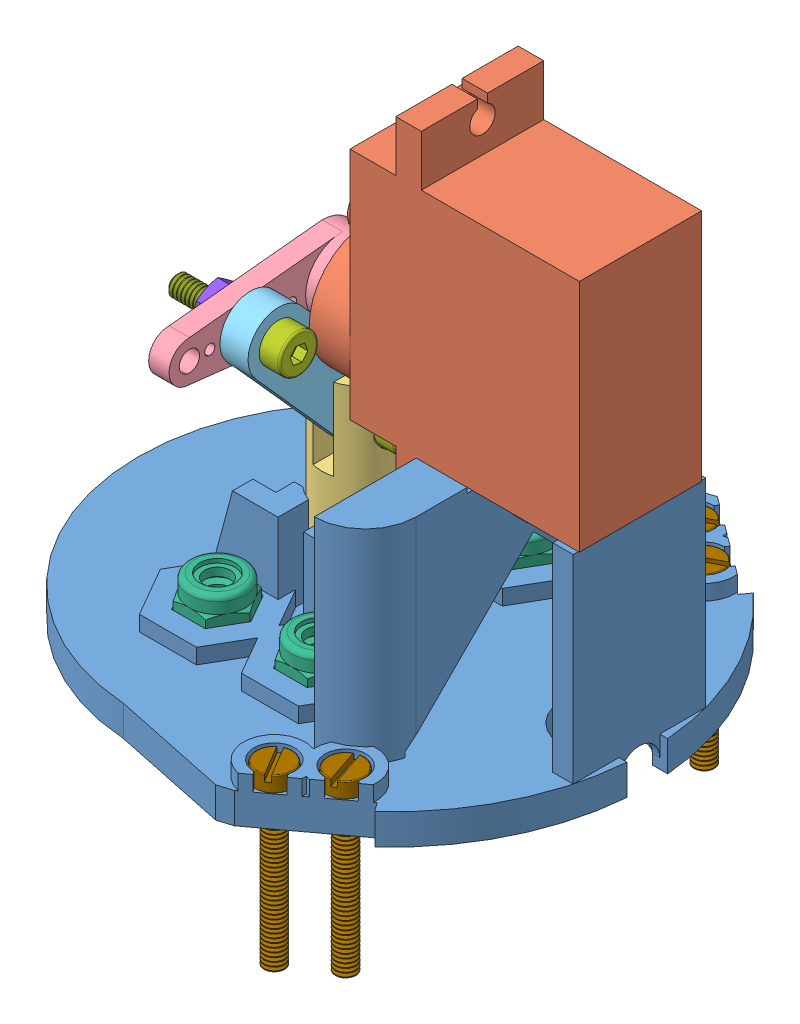
SolidWorks assembly Rückseite, configuration Standard. Lengths in mm.
Overall size (49.92 63.5 48.18).
20 component instances, 10 part files, 43 mates.
Components (placement in the parent):
- Backside-1: Backside [Standard] at (-0.7502 -6.4244 50) size (49.92 23 48.18)
- servo-1: servo [Standard] at (26.7498 39.0756 44) x (0 -1 0) z (0 0 -1) size (33 29.25 12)
- Druecker-1: Druecker [Standard] at (-0.7502 16.0763 50) x (0 0 -1) z (-1 0 0) size (7.5 28 7.5)
- Servo-Arm-1: Servo-Arm [Standard] at (-4.5002 22.0756 50) x (0 0.007015 0.999975) z (0 0.999975 -0.007015) size (20.6 4.3 7.2)
- Hebel2-1: Hebel2 [Standard] at (-1.7502 12.0763 50) x (0 0.745371 0.66665) z (0 0.66665 -0.745371) size (19.5 2.75 6)
- User Library-Mutter DIN-985_-1: User Library-Mutter DIN-985_ [Mutter DIN-985 M3-A2] at (-4.7502 -3.4244 60) x (0 1 0) z (0 0 1) size (4 6.35 5.5)
- User Library-Mutter DIN-985_-2: User Library-Mutter DIN-985_ [Mutter DIN-985 M3-A2] at (5.2498 -3.4244 60) x (0 1 0) z (-0.866025 0 0.5) size (4 6.35 5.5)
- User Library-Mutter DIN-985_-3: User Library-Mutter DIN-985_ [Mutter DIN-985 M3-A2] at (5.2498 -3.4244 40) x (0 1 0) z (-0.866025 0 -0.5) size (4 6.35 5.5)
- User Library-Mutter DIN-985_-4: User Library-Mutter DIN-985_ [Mutter DIN-985 M3-A2] at (-4.7502 -3.4244 40) x (0 1 0) z (-0.866025 0 0.5) size (4 6.35 5.5)
- socket head cap screw 4762_din-2: socket head cap screw 4762_din [ISO 4762 M2 x 10 --- 10S] at (4.4998 12.0763 50) x (-1 0 0) z (0 0.998185 -0.060223) size (12 3.8 3.8)
- socket head cap screw 4762_din-3: socket head cap screw 4762_din [ISO 4762 M2 x 10 --- 10S] at (2.2498 22.1388 58.9998) x (-1 0 0) z (0 -0.636606 -0.77119) size (12 3.8 3.8)
- nut__style_1__m2x0_4__ansi_b18_2_4_1m-1: nut__style_1__m2x0_4__ansi_b18_2_4_1m [Default] at (-4.0002 12.0763 50) x (0 -0.5 -0.866025) z (-1 0 0) size (4.62 4 1.6)
- nut__style_1__m2x0_4__ansi_b18_2_4_1m-2: nut__style_1__m2x0_4__ansi_b18_2_4_1m [Default] at (-6.1002 22.1388 58.9998) x (0 0.584705 0.811246) z (1 0 0) size (4.62 4 1.6)
- slotted cheese head screw_din-1: slotted cheese head screw_din [ISO 1207 - M2 x 16 --- 16S] at (11.3929 -2.0244 70.5635) x (0 -1 0) z (0.511563 0 0.859246) size (17.41 3.8 3.8)
- slotted cheese head screw_din-2: slotted cheese head screw_din [ISO 1207 - M2 x 16 --- 16S] at (11.3929 -2.0244 29.4365) x (0 -1 0) z (-0.876101 0 0.482128) size (17.41 3.8 3.8)
- slotted cheese head screw_din-3: slotted cheese head screw_din [ISO 1207 - M2 x 16 --- 16S] at (15.4084 -2.0244 32.4156) x (0 -1 0) z (-0.890448 0 0.455085) size (17.41 3.8 3.8)
- slotted cheese head screw_din-4: slotted cheese head screw_din [ISO 1207 - M2 x 16 --- 16S] at (15.4084 -2.0244 67.5844) x (0 -1 0) z (0.315666 0 0.94887) size (17.41 3.8 3.8)
- cross fh tapping 7976_din-2: cross fh tapping 7976_din [Tapping screw DIN 7982-ST2.9x6.5-C-Z-S] at (-5.2502 22.0756 50) x (1 0 0) z (0 0.296413 0.95506) size (6.51 5.5 5.5)
- slotted cheese head screw_din-7: slotted cheese head screw_din [ISO 1207 - M2 x 16 --- 16S] at (7.3498 13.0756 50) x (1 0 0) z (0 0.315666 0.94887) size (17.41 3.8 3.8)
- nut__style_1__m2x0_4__ansi_b18_2_4_1m-5: nut__style_1__m2x0_4__ansi_b18_2_4_1m [Default] at (16.2498 13.0756 50) x (0 0.584705 0.811246) z (1 0 0) size (4.62 4 1.6)
Mates (geometry in assembly coordinates):
- Konzentrisch1: concentric anti-aligned: cylinder of Druecker-1 through (-0.7502 -11.9237 50) axis (0 1 0) radius 3.75; cylinder of Backside-1 through (-0.7502 -3.4244 50) axis (0 -1 0) radius 4
- Konzentrisch3: concentric anti-aligned: cylinder of servo-1 through (0.2498 22.0756 50) axis (1 0 0) radius 6; cylinder of Servo-Arm-1 through (-0.2002 22.0756 50) axis (-1 0 0) radius 2.25
- Deckungsgleich9: coincident anti-aligned: plane of Hebel2-1 through (-2.5002 22.1388 58.9998) normal (-1 0 0); plane of Servo-Arm-1 through (-2.5002 22.0756 50) normal (1 0 0)
- Deckungsgleich12: coincident anti-aligned: plane of servo-1 through (-2.5002 22.0756 50) normal (-1 0 0); plane of Servo-Arm-1 through (-2.5002 22.0756 50) normal (1 0 0)
- Konzentrisch5: concentric aligned: cylinder of Hebel2-1 through (0.2498 22.1388 58.9998) axis (-1 0 0) radius 1.15; cylinder of Servo-Arm-1 through (-2.5002 22.1388 58.9998) axis (-1 0 0) radius 0.5
- Deckungsgleich28: coincident anti-aligned: plane of Backside-1 through (-0.7502 -3.4244 50) normal (0 1 0); plane of User Library-Mutter DIN-985_-1 through (-7.4789 -3.4244 60) normal (0 -1 0)
- Deckungsgleich29: coincident anti-aligned: plane of Backside-1 through (-0.7502 -3.4244 50) normal (0 1 0); plane of User Library-Mutter DIN-985_-2 through (3.8855 -3.4244 57.6369) normal (0 -1 0)
- Deckungsgleich31: coincident anti-aligned: plane of Backside-1 through (-0.7502 -3.4244 50) normal (0 1 0); plane of User Library-Mutter DIN-985_-3 through (6.6142 -3.4244 37.6369) normal (0 -1 0)
- Deckungsgleich30: coincident anti-aligned: plane of Backside-1 through (-0.7502 -3.4244 50) normal (0 1 0); plane of User Library-Mutter DIN-985_-4 through (-6.1145 -3.4244 37.6369) normal (0 -1 0)
- Konzentrisch19: concentric anti-aligned: cylinder of Druecker-1 through (3.2498 12.0763 50) axis (-1 0 0) radius 1.1; cylinder of socket head cap screw 4762_din-2 through (36.2498 12.0763 50) axis (1 0 0) radius 1
- Deckungsgleich38: coincident anti-aligned: plane of Hebel2-1 through (0.2498 12.0763 50) normal (1 0 0); plane of socket head cap screw 4762_din-3 through (0.2498 23.604 57.7902) normal (-1 0 0)
- Konzentrisch38: concentric anti-aligned: cylinder of Hebel2-1 through (0.2498 22.1388 58.9998) axis (-1 0 0) radius 1.15; cylinder of socket head cap screw 4762_din-3 through (33.9998 22.1388 58.9998) axis (1 0 0) radius 1
- Deckungsgleich41: coincident anti-aligned: plane of Druecker-1 through (-4.0002 16.0763 50) normal (-1 0 0); plane of nut__style_1__m2x0_4__ansi_b18_2_4_1m-1 through (-4.0002 10.9213 47.9995) normal (1 0 0)
- Konzentrisch49: concentric aligned: circle of socket head cap screw 4762_din-2; circle of nut__style_1__m2x0_4__ansi_b18_2_4_1m-1
- Konzentrisch50: concentric anti-aligned: circle of socket head cap screw 4762_din-3; circle of nut__style_1__m2x0_4__ansi_b18_2_4_1m-2
- Konzentrisch51: concentric aligned: circle of Backside-1; circle of User Library-Mutter DIN-985_-1
- Konzentrisch52: concentric aligned: circle of Backside-1; circle of User Library-Mutter DIN-985_-2
- Konzentrisch53: concentric aligned: circle of Backside-1; circle of User Library-Mutter DIN-985_-4
- Konzentrisch54: concentric aligned: circle of Backside-1; circle of User Library-Mutter DIN-985_-3
- Deckungsgleich40: coincident anti-aligned: plane of Druecker-1 through (2.4998 12.0763 50) normal (1 0 0); plane of socket head cap screw 4762_din-2 through (2.4998 12.1907 51.8966) normal (-1 0 0)
- Konzentrisch59: concentric anti-aligned: cylinder of Backside-1 through (15.4084 -3.4244 32.4156) axis (0 -1 0) radius 1.1; cylinder of slotted cheese head screw_din-3 through (15.4084 23.3756 32.4156) axis (0 1 0) radius 1
- Konzentrisch60: concentric anti-aligned: cylinder of Backside-1 through (11.3929 -3.4244 29.4365) axis (0 -1 0) radius 1.1; cylinder of slotted cheese head screw_din-2 through (11.3929 23.3756 29.4365) axis (0 1 0) radius 1
- Konzentrisch61: concentric anti-aligned: cylinder of Backside-1 through (15.4084 -3.4244 67.5844) axis (0 -1 0) radius 1.1; cylinder of slotted cheese head screw_din-4 through (15.4084 23.3756 67.5844) axis (0 1 0) radius 1
- Konzentrisch62: concentric anti-aligned: cylinder of Backside-1 through (11.3929 -3.4244 70.5635) axis (0 -1 0) radius 1.1; cylinder of slotted cheese head screw_din-1 through (11.3929 23.3756 70.5635) axis (0 1 0) radius 1
- Deckungsgleich42: coincident anti-aligned: plane of Backside-1 through (-0.7502 -3.4244 50) normal (0 1 0); plane of slotted cheese head screw_din-3 through (15.8635 -3.4244 33.306) normal (0 -1 0)
- Deckungsgleich43: coincident anti-aligned: plane of Backside-1 through (-0.7502 -3.4244 50) normal (0 1 0); plane of slotted cheese head screw_din-2 through (11.875 -3.4244 30.3126) normal (0 -1 0)
- Deckungsgleich44: coincident anti-aligned: plane of Backside-1 through (-0.7502 -3.4244 50) normal (0 1 0); plane of slotted cheese head screw_din-1 through (12.2521 -3.4244 70.052) normal (0 -1 0)
- Deckungsgleich45: coincident anti-aligned: plane of Backside-1 through (-0.7502 -3.4244 50) normal (0 1 0); plane of slotted cheese head screw_din-4 through (16.3573 -3.4244 67.2687) normal (0 -1 0)
- Deckungsgleich50: coincident: circle of Servo-Arm-1; cone of cross fh tapping 7976_din-2 through (-3.5502 22.0756 50) axis (1 0 0)
- Parallel2: parallel anti-aligned: plane of Backside-1 through (10.5481 -1.9244 43.4769) normal (-0.866025 0 0.5); plane of User Library-Mutter DIN-985_-3 through (8.4252 0.5766 40) normal (0.866025 0 -0.5)
- Parallel3: parallel anti-aligned: plane of Backside-1 through (3.0481 -1.9244 47.8071) normal (-0.866025 0 0.5); plane of User Library-Mutter DIN-985_-4 through (-1.5748 0.5766 40) normal (0.866025 0 -0.5)
- Parallel4: parallel anti-aligned: plane of Backside-1 through (3.0481 -1.9244 52.1929) normal (-0.866025 0 -0.5); plane of User Library-Mutter DIN-985_-1 through (-3.1625 0.5766 62.75) normal (0.866025 0 0.5)
- Parallel5: parallel anti-aligned: plane of Backside-1 through (10.5481 -1.9244 56.5231) normal (-0.866025 0 -0.5); plane of User Library-Mutter DIN-985_-2 through (6.8375 0.5766 62.75) normal (0.866025 0 0.5)
- Parallel6: parallel anti-aligned: plane of Druecker-1 through (-4.0002 13.2598 52.05) normal (0 -0.866025 -0.5); plane of nut__style_1__m2x0_4__ansi_b18_2_4_1m-1 through (-5.6002 13.2313 52.0005) normal (0 0.866025 0.5)
- Deckungsgleich51: coincident anti-aligned: plane of servo-1 through (11.2498 11.0756 44) normal (1 0 0); plane of Backside-1 through (11.2498 -6.4244 50) normal (-1 0 0)
- Deckungsgleich58: coincident anti-aligned: plane of Backside-1 through (16.2498 16.0756 56.5) normal (0 1 0); plane of servo-1 through (4.2498 16.0756 44) normal (0 -1 0)
- Konzentrisch70: concentric aligned: cylinder of Backside-1 through (16.2498 13.0756 50) axis (-1 0 0) radius 1.1; cylinder of servo-1 through (16.7498 13.0756 50) axis (-1 0 0) radius 1.25
- Konzentrisch71: concentric aligned: cylinder of Druecker-1 through (3.2498 12.0763 50) axis (-1 0 0) radius 1.1; cylinder of Hebel2-1 through (0.2498 12.0763 50) axis (-1 0 0) radius 1.15
- Deckungsgleich59: coincident anti-aligned: plane of Servo-Arm-1 through (-4.5002 22.0756 50) normal (-1 0 0); plane of nut__style_1__m2x0_4__ansi_b18_2_4_1m-2 through (-4.5002 23.4894 60.8738) normal (1 0 0)
- Konzentrisch72: concentric aligned: cylinder of Backside-1 through (16.2498 13.0756 50) axis (-1 0 0) radius 1.1; cylinder of slotted cheese head screw_din-7 through (-18.0502 13.0756 50) axis (-1 0 0) radius 1
- Deckungsgleich60: coincident anti-aligned: plane of servo-1 through (8.7498 11.0756 44) normal (-1 0 0); plane of slotted cheese head screw_din-7 through (8.7498 14.0245 49.6843) normal (1 0 0)
- Deckungsgleich61: coincident anti-aligned: plane of Backside-1 through (16.2498 -6.4244 50) normal (1 0 0); plane of nut__style_1__m2x0_4__ansi_b18_2_4_1m-5 through (16.2498 14.4263 51.874) normal (-1 0 0)
- Konzentrisch73: concentric aligned: cylinder of Backside-1 through (16.2498 13.0756 50) axis (-1 0 0) radius 1.1; cylinder of nut__style_1__m2x0_4__ansi_b18_2_4_1m-5 through (16.2498 13.0756 50) axis (-1 0 0) radius 0.7835
